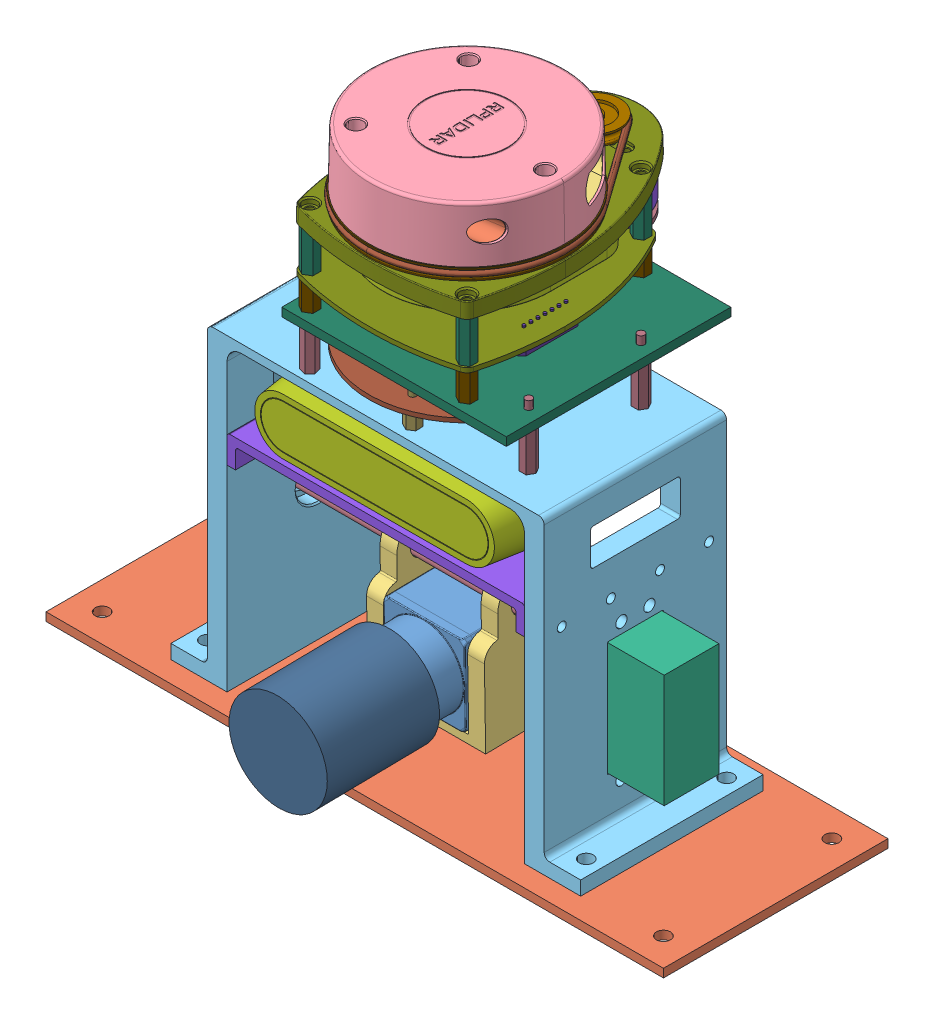
SolidWorks assembly 传感器组合, configuration 默认. Lengths in mm.
Overall size (220 188.6 134.57).
50 component instances, 37 part files, 45 mates.
Components (placement in the parent):
- MV-CE060-10UMUC-1: MV-CE060-10UMUC [默认] at (0 29.3441 9.6254) x (-1 0 0) z (0 0.015888 -0.999874) size (29.75 29.77 48.46)
- 顶部连接板-1: 顶部连接板 [默认] at origin size (220 3 80)
- 工业相机固定座-1: 工业相机固定座 [默认] at (0 12.0052 -0.6514) x (-1 0 0) z (0 0.015888 -0.999874) size (42 51 30)
- 工业相机转轴-1: 工业相机转轴 [默认] at (-60.5 53 0) x (0 0.015888 -0.999874) z (1 0 0) size (20 20 95)
- 激光雷达固定板-1: 激光雷达固定板 [默认] at (0 110 0) size (146 110 65)
- MG995-1: MG995 [默认] at (80 43.15 0) x (0 1 0) z (0 0 1) size (54 43 19.5)
- 摄像头D435-1: 摄像头D435 [默认] at (-0.0406 95.5 8.0001) x (0.999991 0 -0.004275) z (0 -1 0) size (90.1 25.01 25.72)
- D345固定座-1: D345固定座 [默认] at (0 80 17.5) size (106 20 30)
- 舵盘-1: 舵盘 [默认] at (34.5 53 0) x (0 0.015888 -0.999874) z (0 -0.999874 -0.015888) size (20 5 20)
- 镜头-1: 镜头 [默认] at (0 29.2224 17.2844) x (0.876662 0.481046 0.007644) z (0.481107 -0.876551 -0.013928) size (35 50 35)
- MicArrayV2.0-1: MicArrayV2.0 [默认] at (0 121 0) x (0 0 1) z (-1 0 0) size (72 6.8 70)
- 铜柱2.5x8-1: 铜柱2.5x8 [默认] at (-19.9 113 -11.5) size (5.2 14 4.5)
- 铜柱2.5x8-3: 铜柱2.5x8 [默认] at (7.77 113 27.1) x (0.840132 0 -0.542382) z (0.542382 0 0.840132) size (5.2 14 4.5)
- 铜柱2.5x8-7: 铜柱2.5x8 [默认] at (19.9 113 -11.5) size (5.2 14 4.5)
- 铜柱2.5x16-4: 铜柱2.5x16 [默认] at (-28 113 28) x (0.697872 0 -0.716222) z (0.716222 0 0.697872) size (5.2 22 4.5)
- 铜柱2.5x16-8: 铜柱2.5x16 [默认] at (42 113 20) size (5.2 22 4.5)
- 铜柱2.5x16-9: 铜柱2.5x16 [默认] at (42 113 -20) size (5.2 22 4.5)
- 铜柱2.5x16-10: 铜柱2.5x16 [默认] at (-28 113 -28) size (5.2 22 4.5)
- type-C接头-1: type-C接头 [默认] at (-56.8496 95.5012 11.493) x (0 -1 0) z (0.999991 0 -0.004275) size (12.5 6.5 48)
- 顶部扩展-1: 顶部扩展 [默认] at (7 129 -7) size (80 3 80)
- RPLIDAR A1 DevKit-2: RPLIDAR A1 DevKit [默认] at (13.0661 140.904 -69.4738) x (0 0 -1) z (1 0 0) size (102.81 56.6 71.78)
  - RPLIDAR A1 DevKit.igs-1: RPLIDAR A1 DevKit.igs [默认] at origin size (102.81 56.6 71.78)
    - 无线固定平台1.5.igs-1: 无线固定平台1.5.igs [默认] at (-69.4738 21.696 -13.0661) size (96.78 15.15 70.28)
    - 6807.igs-1: 6807.igs [默认] at (-69.4738 23.696 -13.0661) x (1 0 0) z (0 -1 0) size (47 47 7)
    - 无线旋转平台1.5.igs-1: 无线旋转平台1.5.igs [默认] at (-69.4738 25.696 -13.0661) x (0.00451 0 -0.99999) z (0.99999 0 0.00451) size (70.78 21.4 70.78)
    - 激光发射头.igs-1: 激光发射头.igs [默认] at (-94.6291 38.696 -19.9402) x (0.990886 0 -0.134705) z (0.134705 0 0.990886) size (6.5 6.5 21.2)
    - 激光导向槽1.5.igs-1: 激光导向槽1.5.igs [默认] at (-69.4738 29.696 -13.0661) x (-0.99999 0 -0.00451) z (0.00451 0 -0.99999) size (17.83 19.57 21.61)
    - 镜头导向槽1.5.igs-1: 镜头导向槽1.5.igs [默认] at (-69.4738 29.696 -13.0661) x (-0.99999 0 -0.00451) z (0.00451 0 -0.99999) size (22.09 19.65 24.8)
    - 圆台盖1.5.igs-1: 圆台盖1.5.igs [默认] at (-69.4738 47.696 -13.0661) x (0.99999 0 0.00451) z (0.00451 0 -0.99999) size (70 19.5 70)
    - 下隔磁片.igs-1: 下隔磁片.igs [默认] at (-69.4738 12.696 -13.0661) x (0.987093 0 -0.160146) z (0.160146 0 0.987093) size (25 1.2 25)
    - 发射PCB1.5.igs-1: 发射PCB1.5.igs [默认] at (-69.4738 11.696 -13.0661) size (55.5 1 57)
    - 底盖1.5.igs-1: 底盖1.5.igs [默认] at (-69.4738 10.696 -13.0661) size (60.21 11.34 60.96)
    - 电机.igs-1: 电机.igs [默认] at (-23.9738 2.196 -13.0661) x (0 0 -1) z (1 0 0) size (32 30.2 32)
    - 皮带轮1.5.igs-1: 皮带轮1.5.igs [默认] at (-23.9738 24.196 -13.0661) x (0.135455 0 -0.990784) z (0.990784 0 0.135455) size (18 5.5 18)
    - 镜头.igs-1: 镜头.igs [默认] at (-52.5259 38.696 -1.4895) x (0.136926 0.990581 0.000618) z (-0.00451 0 0.99999) size (14 14 11.5)
    - 皮带1-5^无线-RPLIDAR-1.5 DevKit.igs-1: 皮带1-5^无线-RPLIDAR-1.5 DevKit.igs [默认] at (-69.4738 26.196 -13.0661) x (1 0 0) z (0 -1 0) size (90.89 71.78 37.02)
    - 1.25 4pin.igs-1: 1.25 4pin.igs [默认] at (-45.3638 9.296 -13.0661) x (0 0 -1) z (0 -1 0) size (10.15 4.2 4.7)
    - 电机驱动板.igs-1: 电机驱动板.igs [默认] at (-23.9738 -1.404 -13.0661) x (-0.441218 0 -0.8974) z (0.8974 0 -0.441218) size (32 1.6 32)
    - 1.25 3pin.igs-1: 1.25 3pin.igs [默认] at (-36.9138 -3.104 -13.0661) x (0 0 1) z (0 -1 0) size (8.9 5.2 3.4)
    - 螺柱2.igs-1: 螺柱2.igs [默认] at (-97.4738 2.696 14.9339) size (5.77 15 5)
    - 螺柱2.igs-2: 螺柱2.igs [默认] at (-97.4738 2.696 -41.0661) size (5.77 15 5)
    - 螺柱2.igs-3: 螺柱2.igs [默认] at (-27.4738 2.696 -33.0661) size (5.77 15 5)
    - 螺柱2.igs-4: 螺柱2.igs [默认] at (-27.4738 2.696 6.9339) size (5.77 15 5)
    - 固定平台PCB.igs-1: 固定平台PCB.igs [默认] at (-69.4738 2.696 -13.0661) x (1 0 0) z (0 0 -1) size (80.7 4.7 70)
    - 7pin插槽.igs-1: 7pin插槽.igs [默认] at (-69.4738 1.096 14.0339) x (0 -1 0) z (1 0 0) size (8.2 5 20)
    - 螺柱1.igs-1: 螺柱1.igs [默认] at (-27.4738 -8.904 6.9339) size (5.77 10 5)
    - 螺柱1.igs-2: 螺柱1.igs [默认] at (-27.4738 -8.904 -33.0661) size (5.77 10 5)
    - 螺柱1.igs-3: 螺柱1.igs [默认] at (-97.4738 -8.904 14.9339) size (5.77 10 5)
    - 螺柱1.igs-4: 螺柱1.igs [默认] at (-97.4738 -8.904 -41.0661) size (5.77 10 5)
    - 1.25 3pin立贴.igs-1: 1.25 3pin立贴.igs [默认] at (-51.7938 0.996 -13.0661) x (0 0 1) z (1 0 0) size (8.8 4.7 4.36)
Mates (geometry in assembly coordinates):
- 重合1: coordinate: point of 顶部连接板-1
- 重合2: coincident anti-aligned: plane of 顶部连接板-1 through (0 3 0) normal (0 1 0); plane of 激光雷达固定板-1 through (0 3 0) normal (0 -1 0)
- 同心1: concentric anti-aligned: cylinder of 顶部连接板-1 through (-67.5 0 25) axis (0 1 0) radius 1.75; cylinder of 激光雷达固定板-1 through (-67.5 113.001 25) axis (0 -1 0) radius 2.5
- 同心2: concentric anti-aligned: cylinder of 顶部连接板-1 through (-67.5 0 -25) axis (0 1 0) radius 1.75; cylinder of 激光雷达固定板-1 through (-67.5 113.001 -25) axis (0 -1 0) radius 2.5
- 重合4: coincident anti-aligned: plane of MV-CE060-10UMUC-1 through (0 14.9873 0.4969) normal (0 -0.999874 -0.015888); plane of 工业相机固定座-1 through (0 15.0048 -0.6037) normal (0 0.999874 0.015888)
- 同心6: concentric aligned: cylinder of MV-CE060-10UMUC-1 through (-6 19.4135 10.4677) axis (0 -0.999874 -0.015888) radius 0.8; cylinder of 工业相机固定座-1 through (-6 62.825 11.1575) axis (0 -0.999874 -0.015888) radius 1.5
- 同心8: concentric anti-aligned: cylinder of 工业相机固定座-1 through (-21 53 0) axis (1 0 0) radius 5.25; cylinder of 工业相机转轴-1 through (34.5 53 0) axis (-1 0 0) radius 5
- 同心9: concentric anti-aligned: cylinder of 工业相机固定座-1 through (18 62.9987 0.1589) axis (0 -0.999874 -0.015888) radius 1.5; cylinder of 工业相机转轴-1 through (18 43.0013 -0.1589) axis (0 0.999874 0.015888) radius 1.4
- 重合6: coincident anti-aligned: plane of 激光雷达固定板-1 through (53 3 0) normal (-1 0 0); plane of MG995-1 through (53 43.15 0) normal (1 0 0)
- 同心10: concentric anti-aligned: cylinder of 工业相机转轴-1 through (34.5 53 0) axis (-1 0 0) radius 5; cylinder of MG995-1 through (37 53 0) axis (1 0 0) radius 2.9
- 同心11: concentric aligned: cylinder of MG995-1 through (80.001 67.465 5) axis (-1 0 0) radius 2; cylinder of 激光雷达固定板-1 through (73.001 67.465 5) axis (-1 0 0) radius 2
- 重合8: coincident anti-aligned: plane of 摄像头D435-1 through (-29.823 83 18.5036) normal (0 -1 0); plane of D345固定座-1 through (0 83 17.5) normal (0 1 0)
- 同心12: concentric anti-aligned: cylinder of 摄像头D435-1 through (0 83 17.5) axis (0 -1 0) radius 2.5; cylinder of D345固定座-1 through (0 73 17.5) axis (0 1 0) radius 3
- 重合10: coincident anti-aligned: plane of 激光雷达固定板-1 through (53 3 0) normal (-1 0 0); plane of D345固定座-1 through (53 83 2.5) normal (1 0 0)
- 同心13: concentric aligned: cylinder of 激光雷达固定板-1 through (-73 76.5 26.25) axis (1 0 0) radius 1.6; cylinder of D345固定座-1 through (-53 76.5 26.25) axis (1 0 0) radius 1.4
- 同心14: concentric aligned: cylinder of D345固定座-1 through (-53 76.5 8.75) axis (1 0 0) radius 1.4; cylinder of 激光雷达固定板-1 through (-73 76.5 8.75) axis (1 0 0) radius 1.6
- 同心15: concentric aligned: cylinder of MG995-1 through (37 53 0) axis (1 0 0) radius 2.9; cylinder of 舵盘-1 through (37 53 0) axis (1 0 0) radius 2.9
- 同心16: concentric aligned: circle of 工业相机转轴-1; cylinder of 舵盘-1 through (39.5 53.1112 -6.9991) axis (-1 0 0) radius 0.75
- 同心17: concentric anti-aligned: cylinder of 工业相机转轴-1 through (-60.501 49.6117 -7.0547) axis (1 0 0) radius 0.6; cylinder of 舵盘-1 through (39.5 49.6117 -7.0547) axis (-1 0 0) radius 0.75
- 重合11: coincident anti-aligned: plane of 工业相机转轴-1 through (34.5 53 0) normal (1 0 0); plane of 舵盘-1 through (34.5 53 0) normal (-1 0 0)
- 重合12: coincident anti-aligned: plane of MG995-1 through (37 53 0) normal (-1 0 0); plane of 舵盘-1 through (37 53 0) normal (1 0 0)
- 同心18: concentric anti-aligned: cylinder of MV-CE060-10UMUC-1 through (0 29.2572 15.0941) axis (0 -0.015888 0.999874) radius 12.35; cylinder of 镜头-1 through (0 29.0635 27.2832) axis (0 0.015888 -0.999874) radius 12
- 重合13: coincident anti-aligned: plane of MV-CE060-10UMUC-1 through (0 29.0635 27.2832) normal (0 -0.015888 0.999874); plane of 镜头-1 through (0 29.0635 27.2832) normal (0 0.015888 -0.999874)
- 同心19: concentric aligned: cylinder of 激光雷达固定板-1 through (-19.9 2.999 -11.5) axis (0 1 0) radius 1.25; cylinder of MicArrayV2.0-1 through (-19.9 121 -11.5) axis (0 1 0) radius 1
- 同心20: concentric aligned: cylinder of 激光雷达固定板-1 through (7.77 2.999 27.1) axis (0 1 0) radius 1.25; cylinder of MicArrayV2.0-1 through (7.77 121 27.1) axis (0 1 0) radius 1
- 同心21: concentric anti-aligned: cylinder of MicArrayV2.0-1 through (19.9 121 -11.5) axis (0 1 0) radius 1; cylinder of 铜柱2.5x8-7 through (19.9 127 -11.5) axis (0 -1 0) radius 1.25
- 重合14: coincident anti-aligned: plane of MicArrayV2.0-1 through (0 121 0) normal (0 -1 0); plane of 铜柱2.5x8-7 through (19.9 121 -11.5) normal (0 1 0)
- 重合15: coincident anti-aligned: plane of 激光雷达固定板-1 through (0 113 0) normal (0 1 0); plane of 铜柱2.5x8-7 through (19.9 113 -11.5) normal (0 -1 0)
- 同心22: concentric anti-aligned: cylinder of MicArrayV2.0-1 through (-19.9 121 -11.5) axis (0 1 0) radius 1; cylinder of 铜柱2.5x8-1 through (-19.9 127 -11.5) axis (0 -1 0) radius 1.25
- 重合16: coincident anti-aligned: plane of MicArrayV2.0-1 through (0 121 0) normal (0 -1 0); plane of 铜柱2.5x8-1 through (-19.9 121 -11.5) normal (0 1 0)
- 同心23: concentric anti-aligned: cylinder of MicArrayV2.0-1 through (7.77 121 27.1) axis (0 1 0) radius 1; cylinder of 铜柱2.5x8-3 through (7.77 127 27.1) axis (0 -1 0) radius 1.25
- 重合17: coincident anti-aligned: plane of MicArrayV2.0-1 through (0 121 0) normal (0 -1 0); plane of 铜柱2.5x8-3 through (7.77 121 27.1) normal (0 1 0)
- 同心46: concentric aligned: cylinder of 激光雷达固定板-1 through (73.001 18.835 -5) axis (-1 0 0) radius 2; cylinder of MG995-1 through (80.001 18.835 -5) axis (-1 0 0) radius 2
- 同心47: concentric aligned: cylinder of MV-CE060-10UMUC-1 through (6 19.2529 -11.5376) axis (0 -0.999874 -0.015888) radius 0.8; cylinder of 工业相机固定座-1 through (6 63.1745 -10.8397) axis (0 -0.999874 -0.015888) radius 1.5
- 重合39: coincident aligned: plane of 摄像头D435-1 through (-32.5403 95.5 8.139) normal (-0.004275 0 -0.999991); plane of type-C接头-1 through (-32.8637 101.7512 8.1404) normal (-0.004275 0 -0.999991)
- 平行2: parallel anti-aligned: plane of D345固定座-1 through (0 83 17.5) normal (0 1 0); plane of type-C接头-1 through (-32.8637 89.2512 8.1404) normal (0 -1 0)
- 重合40: coincident anti-aligned: plane of 激光雷达固定板-1 through (0 113 0) normal (0 1 0); plane of 铜柱2.5x16-8 through (42 113 20) normal (0 -1 0)
- 同心48: concentric anti-aligned: cylinder of 激光雷达固定板-1 through (42 110 20) axis (0 1 0) radius 1.25; cylinder of 铜柱2.5x16-8 through (42 123 20) axis (0 -1 0) radius 1.25
- 同心49: concentric anti-aligned: cylinder of 激光雷达固定板-1 through (-28 110 28) axis (0 1 0) radius 1.25; cylinder of 铜柱2.5x16-4 through (-28 123 28) axis (0 -1 0) radius 1.25
- 重合41: coincident anti-aligned: plane of 铜柱2.5x16-10 through (-28 129 -28) normal (0 1 0); plane of 顶部扩展-1 through (7 129 -7) normal (0 -1 0)
- 同心53: concentric aligned: circle of RPLIDAR A1 DevKit-2/RPLIDAR A1 DevKit.igs-1/螺柱1.igs-3; cylinder of 顶部扩展-1 through (28 129 28) axis (0 1 0) radius 1.25
- 重合42: coincident anti-aligned: plane of 顶部扩展-1 through (7 132 -7) normal (0 1 0); plane of RPLIDAR A1 DevKit-2/RPLIDAR A1 DevKit.igs-1/螺柱1.igs-3 through (28 132 28) normal (0 -1 0)
- 同心54: concentric aligned: cylinder of 顶部扩展-1 through (-28 129 28) axis (0 1 0) radius 1.25; circle of RPLIDAR A1 DevKit-2/RPLIDAR A1 DevKit.igs-1/螺柱1.igs-4
- 同心55: concentric anti-aligned: cylinder of 铜柱2.5x16-4 through (-28 135 28) axis (0 -1 0) radius 1.25; cylinder of 顶部扩展-1 through (-28 129 28) axis (0 1 0) radius 1.25
- 同心56: concentric aligned: cylinder of 顶部扩展-1 through (-20 129 -42) axis (0 1 0) radius 1.25; circle of RPLIDAR A1 DevKit-2/RPLIDAR A1 DevKit.igs-1/螺柱1.igs-2
